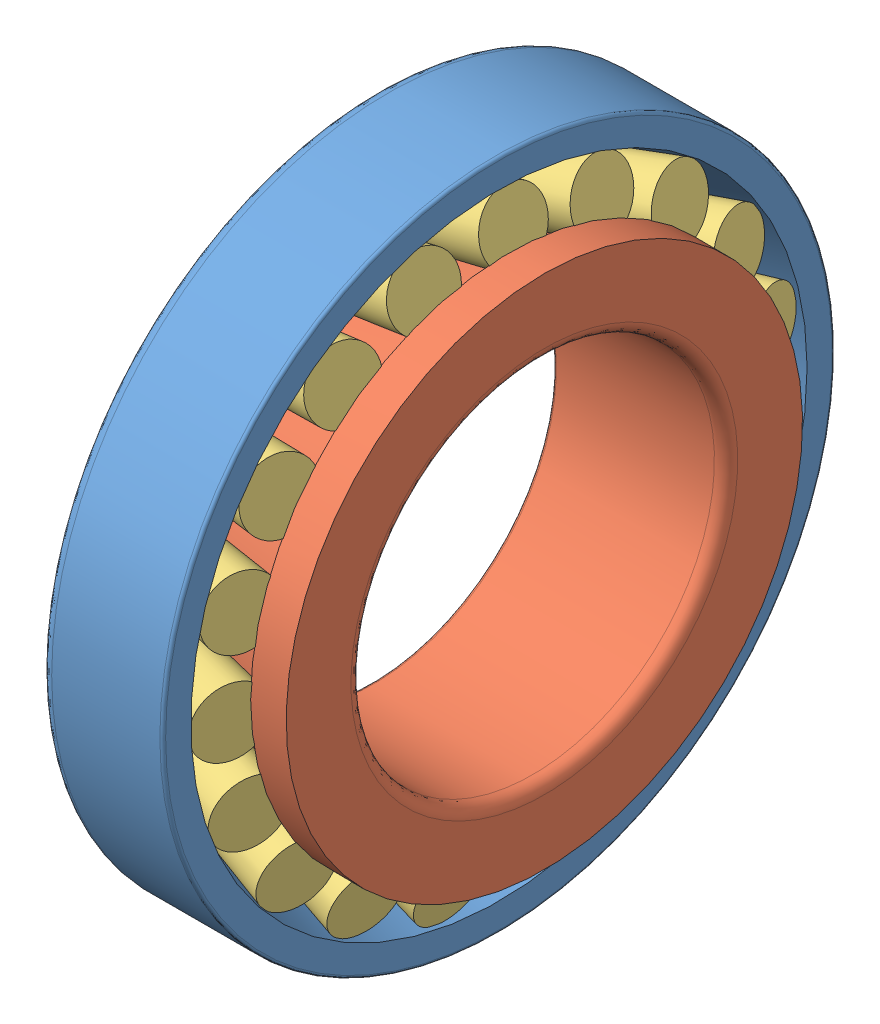
SolidWorks assembly Front Bearing, configuration Default. Lengths in mm.
Overall size (15.08 70.91 66.17).
3 component instances, 3 part files, 4 mates.
Components (placement in the parent):
- Front Cup-1: Front Cup [Default] at origin size (10.72 58.74 58.74)
- Front Cone-1: Front Cone [Default] x (1 0 0) z (0 -0.432041 -0.901854) size (15.08 45.11 45.11)
- Front Rollers-1: Front Rollers [Default] x (1 0 0) z (0 -0.432041 -0.901854) size (11.17 53.47 53.31)
Mates (geometry in assembly coordinates):
- Distance1: distance = 0.3962 mm aligned: plane of Front Cone-1 through (0 -7.8017 -16.2855) normal (-1 0 0); plane of Front Cup-1 through (0.3962 0 25.948) normal (-1 0 0)
- Concentric1: concentric aligned: cylinder of Front Cone-1 through (14.064 0 0) axis (-1 0 0) radius 15.875; cylinder of Front Cup-1 through (6.1354 0 0) axis (-1 0 0) radius 29.3687
- Coincident2: coordinate: point of Front Cup-1; point of assembly
- Coincident3: coordinate: point of Front Cone-1; point of Front Rollers-1
